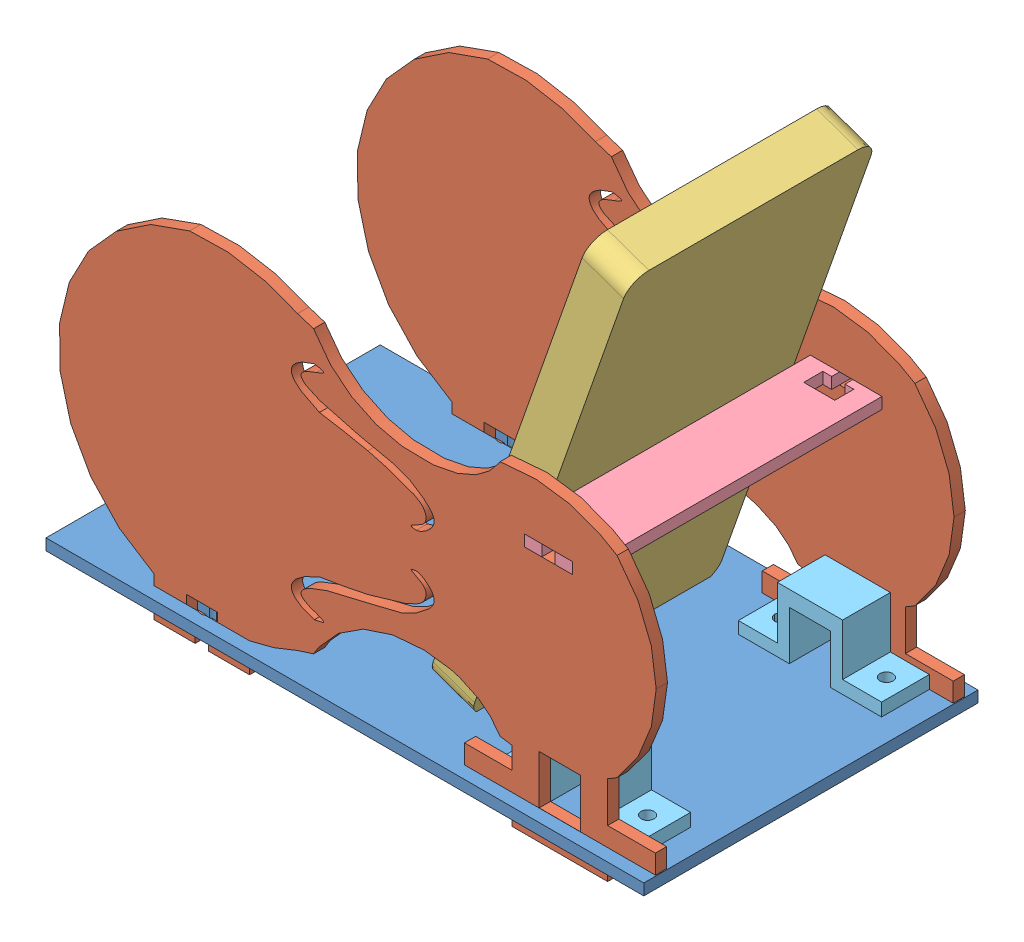
SolidWorks assembly chucar, configuration Default. Lengths in mm.
Overall size (159 132.99 88.9).
7 component instances, 5 part files, 15 mates.
Components (placement in the parent):
- bottom-2: bottom [Default] at (21.8312 25.3515 156.8369) x (1 0 0) z (0 -1 0) size (159 88.9 3)
- half_violin_straight-4: half_violin_straight [Default] at (-13.1006 68.3171 194.9465) x (1 0 0) z (0 0 -1) size (158.97 95.16 3)
- half_violin_straight-5: half_violin_straight [Default] at (-13.1006 68.3171 115.7273) x (1 0 0) z (0 0 -1) size (158.97 95.16 3)
- phone-1: phone [Default] at (49.6913 89.2757 152.959) x (0 0 -1) z (0.943588 -0.331122 0) size (65.79 129.79 11.68)
- deck-1: deck [Default] at (72.6244 83.5571 156.8465) size (19.05 3 82.2)
- motor_holder-1: motor_holder [Default] at (75.6792 31.8515 182.2465) size (38.1 17.14 12.7)
- motor_holder-2: motor_holder [Default] at (75.6792 31.8515 118.7273) size (38.1 17.14 12.7)
Mates (geometry in assembly coordinates):
- Coincident9: coincident anti-aligned: plane of bottom-2 through (62.9792 22.3515 197.9465) normal (0 0 -1); plane of half_violin_straight-4 through (61.3764 36.4294 197.9465) normal (0 0 1)
- Coincident10: coincident anti-aligned: plane of bottom-2 through (88.3792 22.3515 194.9465) normal (-1 0 0); plane of half_violin_straight-4 through (88.3792 25.3515 197.9465) normal (1 0 0)
- Coincident11: coincident anti-aligned: plane of bottom-2 through (21.8312 25.3515 156.8369) normal (0 1 0); plane of half_violin_straight-4 through (88.3792 25.3515 197.9465) normal (0 -1 0)
- Coincident12: coincident anti-aligned: plane of bottom-2 through (76.5856 22.3515 115.7273) normal (0 0 1); plane of half_violin_straight-5 through (61.3764 36.4294 115.7273) normal (0 0 -1)
- Coincident13: coincident anti-aligned: plane of bottom-2 through (21.8312 25.3515 156.8369) normal (0 1 0); plane of half_violin_straight-5 through (88.3792 25.3515 118.7273) normal (0 -1 0)
- Coincident14: coincident anti-aligned: plane of bottom-2 through (62.9792 22.3515 118.7273) normal (1 0 0); plane of half_violin_straight-5 through (62.9792 25.3515 118.7273) normal (-1 0 0)
- Coincident16: coincident aligned: plane of half_violin_straight-4 through (61.3764 36.4294 197.9465) normal (0 0 1); plane of deck-1 through (66.2744 86.5571 197.9465) normal (0 0 1)
- Coincident17: coincident anti-aligned: plane of half_violin_straight-4 through (78.9744 86.5571 194.9465) normal (-1 0 0); plane of deck-1 through (78.9744 86.5571 194.9465) normal (1 0 0)
- Coincident18: coincident anti-aligned: plane of half_violin_straight-4 through (66.2744 86.5571 194.9465) normal (0 -1 0); plane of deck-1 through (72.6244 86.5571 156.8465) normal (0 1 0)
- Coincident19: coincident anti-aligned: plane of half_violin_straight-4 through (61.3764 36.4294 194.9465) normal (0 0 -1); plane of motor_holder-1 through (75.6792 31.8515 194.9465) normal (0 0 1)
- Coincident20: coincident aligned: plane of half_violin_straight-4 through (70.1792 25.3911 194.9465) normal (1 0 0); plane of motor_holder-1 through (70.1792 25.3515 194.9465) normal (1 0 0)
- Coincident21: coincident anti-aligned: plane of bottom-2 through (21.8312 25.3515 156.8369) normal (0 1 0); plane of motor_holder-1 through (94.7292 25.3515 194.9465) normal (0 -1 0)
- Coincident22: coincident anti-aligned: plane of half_violin_straight-5 through (61.3764 36.4294 118.7273) normal (0 0 1); plane of motor_holder-2 through (75.6792 31.8515 118.7273) normal (0 0 -1)
- Coincident23: coincident aligned: plane of half_violin_straight-5 through (70.1792 25.3911 115.7273) normal (1 0 0); plane of motor_holder-2 through (70.1792 25.3515 131.4273) normal (1 0 0)
- Coincident24: coincident anti-aligned: plane of bottom-2 through (21.8312 25.3515 156.8369) normal (0 1 0); plane of motor_holder-2 through (94.7292 25.3515 131.4273) normal (0 -1 0)
